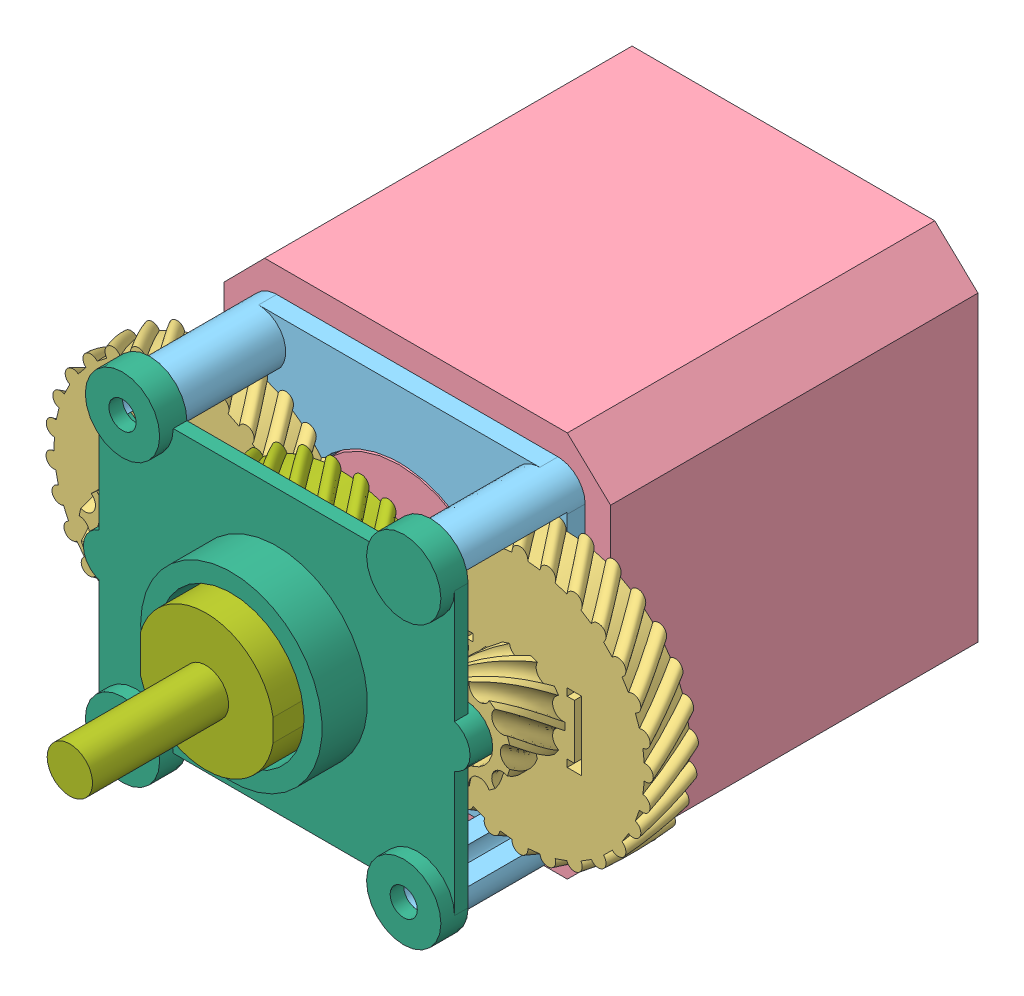
SolidWorks assembly GearStepperMotor, configuration Default. Lengths in mm.
Overall size (68.55 42.6 78.8).
8 component instances, 7 part files, 15 mates.
Components (placement in the parent):
- GearVtulka-1: GearVtulka [Default] at (-0.6199 -0.4892 -3.2366) size (10.23 10.39 19.06)
- GearPressSLDPRT-1: GearPressSLDPRT [Default] at (-0.6199 -0.4892 -2.2366) size (9.53 9.53 12.91)
- GearRot1-1: GearRot1 [Default] at (-19.4334 -1.1462 -8.2366) x (0.994717 0.102659 0) z (0 0 1) size (29.49 29.49 11)
- STP_MTR-1: STP_MTR [Default] at (20.6801 3.6108 -10.7366) x (-1 0 0) z (0 0 -1) size (42.6 42.6 60.5)
- BOTTOM-1: BOTTOM [Default] at (-0.6199 -0.4892 -10.7366) x (0 1 0) z (0 0 1) size (37 42.66 15.5)
- GearRot1-2: GearRot1 [Default] at (18.1935 0.1678 -8.2366) size (29.49 29.49 11)
- GEAR_TOP-1: GEAR_TOP [Default] at (-0.6199 -0.4892 3.2634) size (42.63 39.2 15.9)
- GearRot2-1: GearRot2 [Default] at (-0.6199 -0.4892 -2.2366) size (29.49 29.49 29.8)
Mates (geometry in assembly coordinates):
- Concentric1: concentric: cylinder of GearVtulka-1 through (-0.6199 -0.4892 -2.7366) axis (0 0 -1) radius 2.6; cylinder of GearPressSLDPRT-1 through (-0.6199 -0.4892 9.2634) axis (0 0 -1) radius 3.9
- Coincident1: coincident: plane of GearVtulka-1 through (-0.6199 -0.4892 -2.2366) normal (0 0 1); plane of GearPressSLDPRT-1 through (-0.6199 -0.4892 -2.2366) normal (0 0 -1)
- Parallel4: parallel: plane of GearVtulka-1 through (-0.6199 -0.4892 -8.2366) normal (0 0 -1); plane of GearRot1-1 through (-19.4334 -1.1462 -8.2366) normal (0 0 -1)
- Concentric5: concentric: cylinder of GearVtulka-1 through (-0.6199 -0.4892 -2.2366) axis (0 0 -1) radius 5; cylinder of STP_MTR-1 through (-0.6199 -0.4892 9.2634) axis (0 0 -1) radius 2.5
- Coincident3: coincident: plane of GearPressSLDPRT-1 through (-0.6199 -0.4892 9.2634) normal (0 0 -1); plane of STP_MTR-1 through (-0.6199 -0.4892 9.2634) normal (0 0 1)
- Concentric7: concentric: cylinder of STP_MTR-1 through (-16.1199 -15.9892 -51.2366) axis (0 0 1) radius 1.5; cylinder of BOTTOM-1 through (-16.1199 -15.9892 -8.7366) axis (0 0 -1) radius 1.5
- Concentric8: concentric: cylinder of STP_MTR-1 through (-16.1199 15.0108 -51.2366) axis (0 0 1) radius 1.5; cylinder of BOTTOM-1 through (-16.1199 15.0108 -8.7366) axis (0 0 -1) radius 1.5
- Coincident5: coincident: plane of STP_MTR-1 through (20.6801 20.8108 -10.7366) normal (0 0 1); plane of BOTTOM-1 through (-16.1199 15.0108 -10.7366) normal (0 0 -1)
- Concentric13: concentric: cylinder of GearRot1-1 through (-19.4334 -1.1462 -8.2387) axis (0 0 1) radius 3; cylinder of BOTTOM-1 through (-19.4334 -1.1462 -8.7366) axis (0 0 -1) radius 2.496
- Coincident6: coincident: plane of GearVtulka-1 through (-0.6199 -0.4892 -8.2366) normal (0 0 -1); plane of GearRot1-2 through (18.1935 0.1678 -8.2366) normal (0 0 -1)
- Concentric14: concentric: cylinder of BOTTOM-1 through (18.1935 0.1678 -8.7366) axis (0 0 -1) radius 2.5302; cylinder of GearRot1-2 through (18.1935 0.1678 -8.2387) axis (0 0 1) radius 3
- Concentric17: concentric: cylinder of BOTTOM-1 through (-16.1199 -15.9892 -8.7366) axis (0 0 -1) radius 3; cylinder of GEAR_TOP-1 through (-16.1199 -15.9892 4.7634) axis (0 0 -1) radius 3.1
- Coincident8: coincident: plane of BOTTOM-1 through (-16.1199 -15.9892 4.7634) normal (0 0 1); plane of GEAR_TOP-1 through (-16.1199 -15.9892 4.7634) normal (0 0 -1)
- Concentric18: concentric: cylinder of GearPressSLDPRT-1 through (-0.6199 -0.4892 9.2634) axis (0 0 -1) radius 3.9; cylinder of GearRot2-1 through (-0.6199 -0.4892 2.7709) axis (0 0 -1) radius 6.1
- Coincident9: coincident: plane of GearVtulka-1 through (-0.6199 -0.4892 -2.2366) normal (0 0 1); plane of GearRot2-1 through (-0.6199 -0.4892 -2.2366) normal (0 0 -1)
